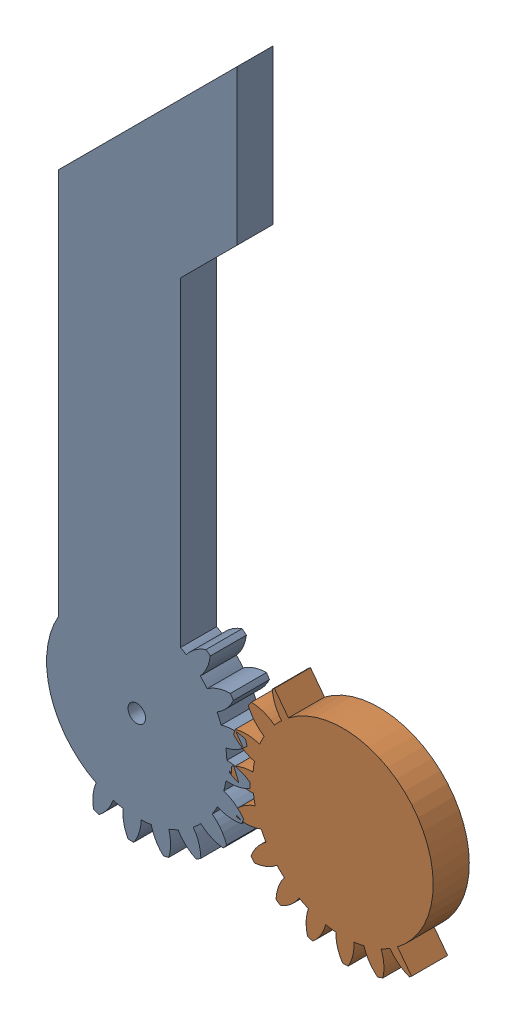
SolidWorks assembly assem1_claw_gripper, configuration Default. Lengths in mm.
Overall size (133.49 162.71 7).
2 component instances, 2 part files, 4 mates.
Components (placement in the parent):
- part1_claw_left_v1-2: part1_claw_left_v1 [Metric - Spur gear 2M 20T 20PA 15FW ---S20N75H50L1N] at (-20 0 8) x (0 0 -1) z (0.5 0.866025 0) size (7 76.81 133.95)
- part1_claw_right_v1-3: part1_claw_right_v1 [Metric - Spur gear 2M 20T 20PA 15FW ---S20N75H50L1N] at (20 0 -15) x (0 0 1) z (-0.472605 0.881274 0) size (7 39.31 43.54)
Mates (geometry in assembly coordinates):
- Concentric2: concentric: part1_claw_left_v1-2
- Coincident1: coincident: part1_claw_left_v1-2
- Coincident2: coincident: part1_claw_right_v1-3
- Parallel1: parallel: part1_claw_left_v1-2
